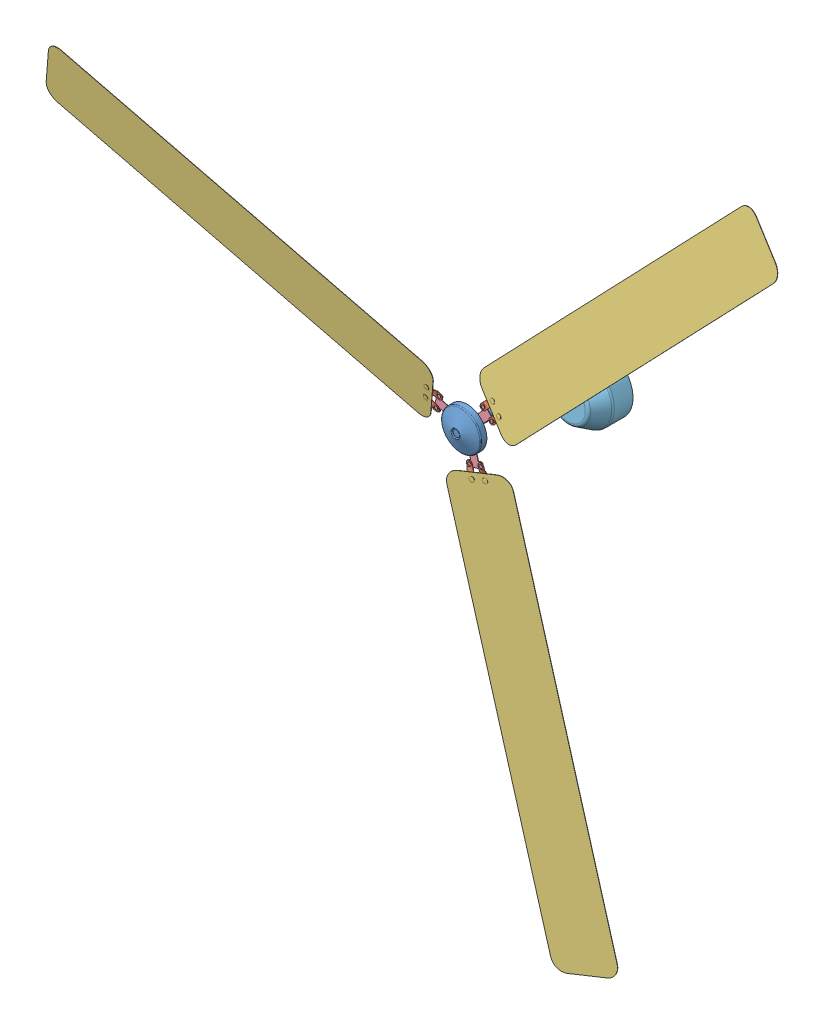
SolidWorks assembly 装配体2, configuration 默认. Lengths in mm.
Overall size (1886.44 1907.53 316.64).
17 component instances, 8 part files, 17 mates.
Components (placement in the parent):
- 承体-1: 承体 [默认] at (-54.7544 88.757 23.5716) x (-0.278927 0.960312 0) z (0 0 1) size (100 100 129.14)
- 扇叶-1: 扇叶 [默认] at (492.6608 719.5925 253.8343) x (-0.692191 -0.721714 0) z (-0.125324 0.120198 0.984808) size (1083.32 150 18.19)
  - 连片2-2: 连片2 [默认] at (748.0846 16.0271 -233.9182) x (1 0 0) z (0 -0.004807 0.999988) size (45 46.91 8.86)
  - 扇叶-2: 扇叶 [默认] at (243.6489 1.0256 -233.2537) size (1000 150 2.96)
  - 连片-1: 连片 [默认] at (840.0599 10.7885 -236.7326) x (-0.5 -0.852869 0.150384) z (0 0.173648 0.984808) size (61.68 68.45 3.01)
- 扇叶-2: 扇叶 [默认] at (-874.7815 247.4148 253.8343) x (0.971118 -0.238598 0) z (-0.041432 -0.168633 0.984808) size (1083.32 150 18.19)
  - 连片2-2: 连片2 [默认] at (748.0846 16.0271 -233.9182) x (1 0 0) z (0 -0.004807 0.999988) size (45 46.91 8.86)
  - 扇叶-2: 扇叶 [默认] at (243.6489 1.0256 -233.2537) size (1000 150 2.96)
  - 连片-1: 连片 [默认] at (840.0599 10.7885 -236.7326) x (-0.5 -0.852869 0.150384) z (0 0.173648 0.984808) size (61.68 68.45 3.01)
- 扇叶-3: 扇叶 [默认] at (217.8576 -700.7362 253.8343) x (-0.278927 0.960312 0) z (0.166756 0.048435 0.984808) size (1083.32 150 18.19)
  - 连片2-2: 连片2 [默认] at (748.0846 16.0271 -233.9182) x (1 0 0) z (0 -0.004807 0.999988) size (45 46.91 8.86)
  - 扇叶-2: 扇叶 [默认] at (243.6489 1.0256 -233.2537) size (1000 150 2.96)
  - 连片-1: 连片 [默认] at (840.0599 10.7885 -236.7326) x (-0.5 -0.852869 0.150384) z (0 0.173648 0.984808) size (61.68 68.45 3.01)
- 电机-1: 电机 [默认] at (1.7441 74.671 -213.9284) x (0.980747 0.195284 0) z (0 0 -1) size (150 150 90)
- 轴-1: 轴 [默认] at (1.7441 74.671 -263.9284) x (0.980747 0.195284 0) z (0 0 1) size (30 30 225)
- 轮-1: 轮 [默认] at (1.7441 74.671 -38.9284) x (-0.195284 0.980747 0) z (0 0 -1) size (40 40 15)
- 键-1: 键 [默认] at (0.3771 81.5363 -43.237) x (0 0 1) z (-0.195284 0.980747 0) size (15 5 6)
Mates (geometry in assembly coordinates):
- 重合1: coincident anti-aligned: plane of 承体-1 through (-54.7544 88.757 23.5716) normal (0 0 -1); plane of 扇叶-3/连片-1 through (-52.5211 -38.896 23.5716) normal (0 0 1)
- 重合2: coincident aligned: circle of 承体-1; circle of 扇叶-3/连片-1
- 重合3: coincident anti-aligned: cylinder of 承体-1 through (-60.6378 55.2356 17.5716) axis (0 0 1) radius 4; circle of 扇叶-3/连片-1
- 重合4: coincident anti-aligned: plane of 承体-1 through (-54.7544 88.757 23.5716) normal (0 0 -1); plane of 扇叶-2/连片-1 through (-166.4219 150.6495 23.5716) normal (0 0 1)
- 重合6: coincident aligned: circle of 承体-1; circle of 扇叶-2/连片-1
- 重合7: coincident aligned: circle of 承体-1; circle of 扇叶-2/连片-1
- 重合8: coincident aligned: circle of 承体-1; circle of 扇叶-1/连片-1
- 重合9: coincident aligned: circle of 承体-1; circle of 扇叶-1/连片-1
- 重合10: coincident anti-aligned: plane of 轴-1 through (0.3771 81.5363 -55.497) normal (-0.195284 0.980747 0); plane of 键-1 through (0.3771 81.5363 -55.497) normal (0.195284 -0.980747 0)
- 重合11: coincident anti-aligned: plane of 轴-1 through (-0.6862 99.6779 -55.497) normal (-0.980747 -0.195284 0); plane of 键-1 through (1.6572 87.909 -55.497) normal (0.980747 0.195284 0)
- 同心1: concentric aligned: cylinder of 轴-1 through (-3.138 99.1897 -55.497) axis (0.195284 -0.980747 0) radius 2.5; cylinder of 键-1 through (-0.7946 87.4207 -55.497) axis (0.195284 -0.980747 0) radius 2.5
- 重合13: coincident anti-aligned: plane of 轮-1 through (-0.7946 87.4207 -54.664) normal (0.195284 -0.980747 0); plane of 键-1 through (-0.7946 87.4207 -55.497) normal (-0.195284 0.980747 0)
- 重合14: coincident anti-aligned: plane of 轮-1 through (-3.2465 86.9325 -54.664) normal (0.980747 0.195284 0); plane of 键-1 through (-3.2465 86.9325 -55.497) normal (-0.980747 -0.195284 0)
- 重合15: coincident aligned: plane of 轴-1 through (1.7441 74.671 -38.9284) normal (0 0 1); plane of 轮-1 through (1.7441 74.671 -38.9284) normal (0 0 1)
- 重合16: coincident aligned: plane of 电机-1 through (1.7441 74.671 -263.9284) normal (0 0 -1); plane of 轴-1 through (1.7441 74.671 -263.9284) normal (0 0 -1)
- 重合17: coincident aligned: circle of 电机-1; circle of 轴-1
- 距离1: distance = 37.5 mm anti-aligned: plane of 轮-1 through (1.7441 74.671 -38.9284) normal (0 0 1); plane of 承体-1 through (-54.7544 88.757 -76.4284) normal (0 0 -1); line of 承体-1 through (-37.1176 0.1827 -32.0719) axis (0 0 1)
